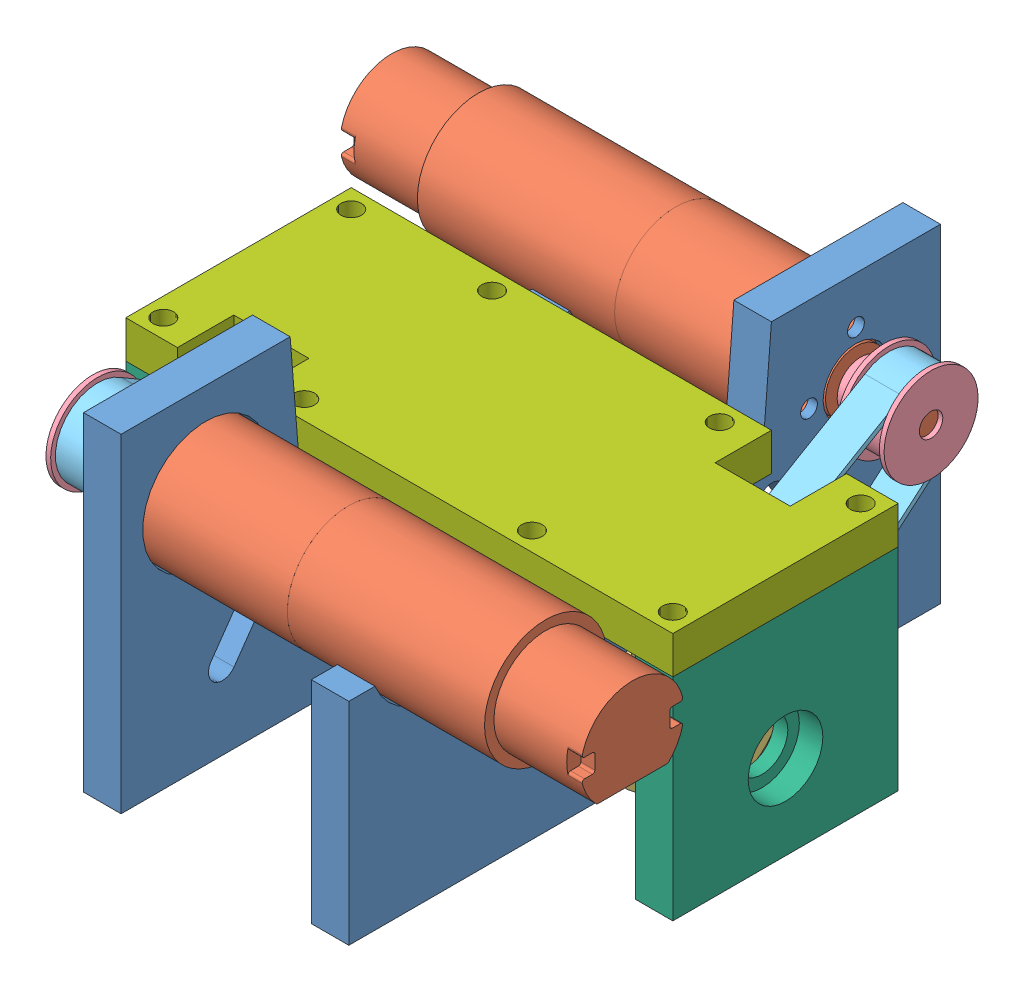
SolidWorks assembly Assemblage bloc moteur, configuration Défaut. Lengths in mm.
Overall size (141.3 70 126).
15 component instances, 7 part files, 6 mates.
Components (placement in the parent):
- Assemblage Moteur BRS-1: Assemblage Moteur BRS [Défaut] at (26.8067 -7.8695 128.9) size (128.9 70 126)
  - Support Moteur BRS-1: Support Moteur BRS [Défaut] at (-7.2218 -30.0825 126) size (8 70 126)
  - Moteur faulhaber D26 BRS Access-1: Moteur faulhaber D26 BRS Access [Défaut] at (-37.6218 19.9175 49) x (0 0 -1) z (1 0 0) size (26 26 113.9)
  - Poulie D32 BRS-1: Poulie D32 BRS [Défaut] at (16.7782 -12.0825 94) x (0 0 1) z (-1 0 0) size (32 32 15.5)
  - Poulie D20 BRS-1: Poulie D20 BRS [Défaut] at (16.7782 19.9175 49) x (0 0.974536 0.224231) z (-1 0 0) size (20 20 15)
  - Courroie tendu BRS-1: Courroie tendu BRS [Défaut] at (15.7782 -12.0825 94) x (0 0 1) z (-1 0 0) size (68 55 8)
  - Support Axe Roue BRS-1: Support Axe Roue BRS [Défaut] at (22.7782 -30.0825 118) size (8 45 48)
- Assemblage Moteur BRS-2: Assemblage Moteur BRS [Défaut] at (-28.137 -7.8695 316.9) x (-1 0 0) z (0 0 -1) size (128.9 70 126)
  - Support Moteur BRS-1: Support Moteur BRS [Défaut] at (-7.2218 -30.0825 126) size (8 70 126)
  - Moteur faulhaber D26 BRS Access-1: Moteur faulhaber D26 BRS Access [Défaut] at (-37.6218 19.9175 49) x (0 0 -1) z (1 0 0) size (26 26 113.9)
  - Poulie D32 BRS-1: Poulie D32 BRS [Défaut] at (16.7782 -12.0825 94) x (0 0 1) z (-1 0 0) size (32 32 15.5)
  - Poulie D20 BRS-1: Poulie D20 BRS [Défaut] at (16.7782 19.9175 49) x (0 0.974536 0.224231) z (-1 0 0) size (20 20 15)
  - Courroie tendu BRS-1: Courroie tendu BRS [Défaut] at (15.7782 -12.0825 94) x (0 0 1) z (-1 0 0) size (68 55 8)
  - Support Axe Roue BRS-1: Support Axe Roue BRS [Défaut] at (22.7782 -30.0825 118) size (8 45 48)
- Support Dessus Moteur Axe BRS-1: Support Dessus Moteur Axe BRS [Défaut] at (-58.9152 7.048 246.9) size (116.5 8 48)
Mates (geometry in assembly coordinates):
- Coaxiale1: concentric aligned: cylinder of Assemblage Moteur BRS-1/Support Moteur BRS-1 through (29.5848 12.048 267.9) axis (-1 0 0) radius 13.4; cylinder of Assemblage Moteur BRS-2/Moteur faulhaber D26 BRS Access-1 through (51.4848 12.048 267.9) axis (-1 0 0) radius 13
- Parallèle1: parallel aligned: line of Assemblage Moteur BRS-1/Support Moteur BRS-1 through (19.5848 -37.952 159.9) axis (0 0 1); line of Assemblage Moteur BRS-2/Support Moteur BRS-1 through (-28.9152 -37.952 159.9) axis (0 0 1)
- Coaxiale2: concentric anti-aligned: circle of Assemblage Moteur BRS-1/Support Axe Roue BRS-1; circle of Support Dessus Moteur Axe BRS-1
- Coïncidente3: coincident anti-aligned: plane of Assemblage Moteur BRS-1/Support Moteur BRS-1 through (29.5848 7.048 254.9) normal (0 1 0); plane of Support Dessus Moteur Axe BRS-1 through (-58.9152 7.048 246.9) normal (0 -1 0)
- Coaxiale3: concentric anti-aligned: circle of Assemblage Moteur BRS-1/Support Axe Roue BRS-1; circle of Support Dessus Moteur Axe BRS-1
- Coaxiale4: concentric anti-aligned: cylinder of Assemblage Moteur BRS-2/Support Axe Roue BRS-1 through (-54.9152 -7.952 202.9) axis (0 1 0) radius 2; cylinder of Support Dessus Moteur Axe BRS-1 through (-54.9152 15.048 202.9) axis (0 -1 0) radius 2.2
